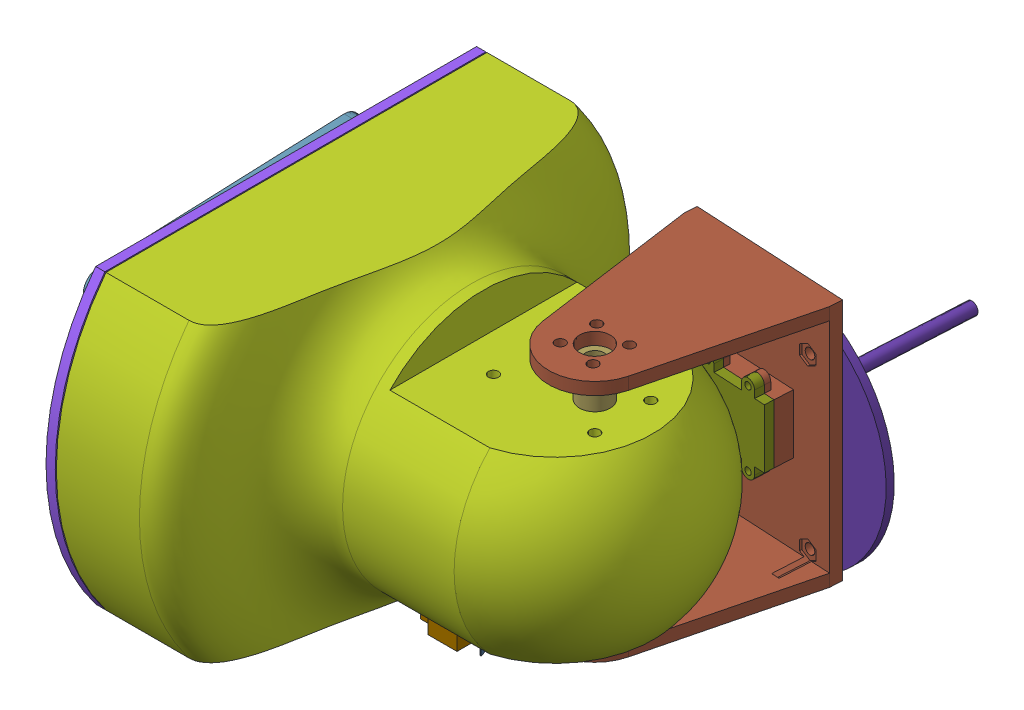
SolidWorks assembly 太阳追踪器, configuration 默认. Lengths in mm.
Overall size (166.51 156 196.42).
44 component instances, 17 part files, 44 mates.
Components (placement in the parent):
- solar_tracer.step-1: solar_tracer.step [默认] at (-191.2949 -153.4039 81.4221) x (0 0 1) z (1 0 0) size (45.95 61.34 13.6)
  - 2.54mm 1x4P.step-1: 2.54mm 1x4P.step [默认] at (-1.796 0.445 0.15) x (0 1 0) z (0 0 1) size (12.02 8.1 13.6)
    - COMPOUND.step-1: COMPOUND.step [默认] at origin size (12.02 8.1 13.6)
  - 2.54mm 1x4P.step-2: 2.54mm 1x4P.step [默认] at (33.272 -1.747 0.15) x (-1 0 0) z (0 0 1) size (12.02 8.1 13.6)
    - COMPOUND.step-1: COMPOUND.step [默认] at origin size (12.02 8.1 13.6)
  - ESP32-S3-WROOM-1.step-1: ESP32-S3-WROOM-1.step [默认] at (20.25 48 1.65) x (0 -1 0) z (0 0 1) size (18 25.5 3.1)
    - COMPOUND-0.step-1: COMPOUND-0.step [默认] at origin size (18 25.5 3.1)
  - 2.54mm 1x2P.step-1: 2.54mm 1x2P.step [默认] at (-1.8 17.8125 0.15) x (0 1 0) z (0 0 1) size (6.95 8.1 13.6)
    - COMPOUND-1.step-1: COMPOUND-1.step [默认] at origin size (6.95 8.1 13.6)
  - 2.54mm 1x2P.step-2: 2.54mm 1x2P.step [默认] at (9.537 62.812 0.15) size (6.95 8.1 13.6)
    - COMPOUND-1.step-1: COMPOUND-1.step [默认] at origin size (6.95 8.1 13.6)
  - 2.54mm 1x4P.step-3: 2.54mm 1x4P.step [默认] at (-1.796 27.7513 0.15) x (0 1 0) z (0 0 1) size (12.02 8.1 13.6)
    - COMPOUND.step-1: COMPOUND.step [默认] at origin size (12.02 8.1 13.6)
  - 2.54mm 1x2P.step-3: 2.54mm 1x2P.step [默认] at (-1.8 10.4038 0.15) x (0 1 0) z (0 0 1) size (6.95 8.1 13.6)
    - COMPOUND-1.step-1: COMPOUND-1.step [默认] at origin size (6.95 8.1 13.6)
  - solar_tracer PCB.step-1: solar_tracer PCB.step [默认] at origin size (40 61 1.6)
- 2814300907JGY-370编码器.STEP-1: 2814300907JGY-370编码器.STEP [默认] at (-155.7925 -163.2626 64.545) size (84.5 46.28 37.08)
  - JGY-370 -636.STEP-1: JGY-370 -636.STEP [默认] at (41.3412 1.3595 0) size (46 38.5 32)
  - 370______.STEP-1: 370______.STEP [默认] at (-12.4588 -9.7405 2.5) x (1 0 0) z (0 -0.481816 0.876272) size (50 24.4 26.7)
- 上壳-1: 上壳 [默认] at (-146.4513 -183.9031 64.495) x (0 0 1) z (0 1 0) size (156 127 156)
- 2814300907JGY-370编码器.STEP-2: 2814300907JGY-370编码器.STEP [默认] at (-198.4354 -183.9031 15.1538) x (0 0 1) z (0 -1 0) size (84.5 46.28 37.08)
  - JGY-370 -636.STEP-1: JGY-370 -636.STEP [默认] at (41.3412 1.3595 0) size (46 38.5 32)
  - 370______.STEP-1: 370______.STEP [默认] at (-12.4588 -9.7405 2.5) x (1 0 0) z (0 -0.481816 0.876272) size (50 24.4 26.7)
- 底板-1: 底板 [默认] at (-206.7949 -183.9031 64.495) x (0 1 0) z (0 0 -1) size (95 7.8 156)
- SS_01GL_E.step-1: SS_01GL_E.step [默认] at (-130.7023 -217.1031 42.1141) x (0 0 -1) z (0 -1 0) size (19.8 20 6.4)
  - SS_01GL_E_BASE.step-1: SS_01GL_E_BASE.step [默认] at origin size (19.8 14.87 6.4)
  - SS_01GL_E_ACTUATOR.step-1: SS_01GL_E_ACTUATOR.step [默认] at (-11.5 7.7 0) size (15.84 5.9 4)
- U型板-1: U型板 [默认] at (-103.7822 -178.4031 14.6163) x (0.053382 0 -0.998574) z (0 1 0) size (69 50 79)
- SS_01GL_E.step-2: SS_01GL_E.step [默认] at (-130.7023 -217.1031 86.8759) x (0 0 1) z (0 1 0) size (19.8 20 6.4)
  - SS_01GL_E_BASE.step-1: SS_01GL_E_BASE.step [默认] at origin size (19.8 14.87 6.4)
  - SS_01GL_E_ACTUATOR.step-1: SS_01GL_E_ACTUATOR.step [默认] at (-11.5 7.7 0) size (15.84 5.9 4)
- 法兰-1: 法兰 [默认] at (-106.4513 -142.9031 64.545) x (-0.053382 0 0.998574) z (0.998574 0 0.053382) size (22 11.6 22)
- 法兰-2: 法兰 [默认] at (-218.7949 -183.9031 64.495) x (0 -0.678155 -0.734919) z (0 -0.734919 0.678155) size (22 11.6 22)
- SS_01GL_E.step-3: SS_01GL_E.step [默认] at (-209.9949 -172.6539 95.4221) x (0 0.34202 0.939693) z (-1 0 0) size (19.8 20 6.4)
  - SS_01GL_E_BASE.step-1: SS_01GL_E_BASE.step [默认] at origin size (19.8 14.87 6.4)
  - SS_01GL_E_ACTUATOR.step-1: SS_01GL_E_ACTUATOR.step [默认] at (-11.5 7.7 0) size (15.84 5.9 4)
- SS_01GL_E.step-4: SS_01GL_E.step [默认] at (-209.9949 -195.1523 95.4221) x (0 -0.34202 0.939693) z (1 0 0) size (19.8 20 6.4)
  - SS_01GL_E_BASE.step-1: SS_01GL_E_BASE.step [默认] at origin size (19.8 14.87 6.4)
  - SS_01GL_E_ACTUATOR.step-1: SS_01GL_E_ACTUATOR.step [默认] at (-11.5 7.7 0) size (15.84 5.9 4)
- pcb支架-1: pcb支架 [默认] at (-193.7949 -183.9039 101.4221) x (0 -1 0) z (-1 0 0) size (71 76 12.5)
- 底座-1: 底座 [默认] at (-226.7949 -183.9031 64.495) x (0 -0.999194 -0.040138) z (0 -0.040138 0.999194) size (57 8 90)
- 轴套-1: 轴套 [默认] at (-106.4513 -217.9031 64.495) x (0.904343 0 0.426806) z (-0.426806 0 0.904343) size (9.7 5 9.7)
- imu盖板-1: imu盖板 [默认] at (-104.1025 -178.4031 20.6078) x (0 1 0) z (-0.053382 0 0.998574) size (28.5 25.2 6)
- 太阳指向盘-1: 太阳指向盘 [默认] at (-103.5687 -183.9031 10.622) x (0 -1 0) z (0.053382 0 -0.998574) size (80 80 62.5)
Mates (geometry in assembly coordinates):
- 同心6: concentric anti-aligned: cylinder of 2814300907JGY-370编码器.STEP-1/JGY-370 -636.STEP-1 through (-97.4513 -157.9031 73.595) axis (0 1 0) radius 1.25; cylinder of 上壳-1 through (-97.4513 -105.9031 73.595) axis (0 -1 0) radius 1.65
- 平行4: parallel anti-aligned: plane of 2814300907JGY-370编码器.STEP-1/JGY-370 -636.STEP-1 through (-137.4513 -182.4031 78.545) normal (-1 0 0); plane of 上壳-1 through (-142.7023 -141.9031 -13.505) normal (1 0 0)
- 重合5: coincident anti-aligned: plane of 2814300907JGY-370编码器.STEP-1/JGY-370 -636.STEP-1 through (-130.5513 -157.9031 55.495) normal (0 1 0); plane of 上壳-1 through (-119.4513 -157.9031 64.495) normal (0 -1 0)
- 同心11: concentric anti-aligned: cylinder of 上壳-1 through (-146.4513 -183.9031 64.495) axis (-1 0 0) radius 42; cylinder of 2814300907JGY-370编码器.STEP-2/JGY-370 -636.STEP-1 through (-217.2949 -183.9031 64.495) axis (1 0 0) radius 3
- 平行6: parallel aligned: plane of 上壳-1 through (-157.5128 -229.4031 64.4207) normal (0 1 0); plane of 2814300907JGY-370编码器.STEP-2/JGY-370 -636.STEP-1 through (-179.2949 -167.9031 35.495) normal (0 1 0)
- 同心12: concentric aligned: cylinder of 上壳-1 through (-146.4513 -183.9031 64.495) axis (-1 0 0) radius 76.3; cylinder of 底板-1 through (-198.9949 -183.9031 64.495) axis (-1 0 0) radius 75.8
- 平行7: parallel aligned: plane of 上壳-1 through (-203.4513 -136.4031 2.6262) normal (0 1 0); plane of 底板-1 through (-198.9949 -138.6031 64.495) normal (0 1 0)
- 重合9: coincident anti-aligned: plane of 2814300907JGY-370编码器.STEP-2/JGY-370 -636.STEP-1 through (-203.7949 -174.8531 73.495) normal (-1 0 0); plane of 底板-1 through (-203.7949 -183.9031 64.495) normal (1 0 0)
- 同心13: concentric anti-aligned: cylinder of 2814300907JGY-370编码器.STEP-1/JGY-370 -636.STEP-1 through (-106.4513 -144.4031 64.545) axis (0 -1 0) radius 3; cylinder of U型板-1 through (-106.4513 -142.9031 64.545) axis (0 1 0) radius 5
- 同心14: concentric anti-aligned: cylinder of 2814300907JGY-370编码器.STEP-1/JGY-370 -636.STEP-1 through (-106.4513 -144.4031 64.545) axis (0 -1 0) radius 3; cylinder of 法兰-1 through (-106.4513 -142.9031 64.545) axis (0 1 0) radius 5
- 重合11: coincident anti-aligned: plane of U型板-1 through (-106.4513 -142.9031 64.545) normal (0 -1 0); plane of 法兰-1 through (-106.6114 -142.9031 67.5408) normal (0 1 0)
- 距离2: distance = 13 mm anti-aligned: plane of 2814300907JGY-370编码器.STEP-1/JGY-370 -636.STEP-1 through (-97.4513 -157.9031 55.495) normal (0 1 0); plane of 法兰-1 through (-107.0385 -144.9031 75.5293) normal (0 -1 0)
- 同心15: concentric anti-aligned: cylinder of 2814300907JGY-370编码器.STEP-2/JGY-370 -636.STEP-1 through (-217.2949 -183.9031 64.495) axis (1 0 0) radius 3; cylinder of 法兰-2 through (-218.7949 -183.9031 64.495) axis (-1 0 0) radius 5
- 距离3: distance = 13 mm anti-aligned: plane of 2814300907JGY-370编码器.STEP-2/JGY-370 -636.STEP-1 through (-203.7949 -174.8531 73.495) normal (-1 0 0); plane of 法兰-2 through (-216.7949 -191.3628 56.4109) normal (1 0 0)
- 重合20: coincident anti-aligned: plane of 底板-1 through (-206.7949 -183.9031 64.495) normal (-1 0 0); plane of SS_01GL_E.step-3/SS_01GL_E_BASE.step-1 through (-206.7949 -173.2247 101.1636) normal (1 0 0)
- 同心16: concentric anti-aligned: cylinder of 上壳-1 through (-130.7023 -206.6504 86.8759) axis (0 -1 0) radius 1.15; cylinder of SS_01GL_E.step-2/SS_01GL_E_BASE.step-1 through (-130.7023 -220.3031 86.8759) axis (0 1 0) radius 1.175
- 同心17: concentric anti-aligned: cylinder of 上壳-1 through (-130.7023 -206.6504 77.3759) axis (0 -1 0) radius 1.15; cylinder of SS_01GL_E.step-2/SS_01GL_E_BASE.step-1 through (-130.7023 -220.3031 77.3759) axis (0 1 0) radius 1.25
- 同心18: concentric aligned: cylinder of 上壳-1 through (-130.7023 -206.6504 42.1141) axis (0 -1 0) radius 1.15; cylinder of SS_01GL_E.step-1/SS_01GL_E_BASE.step-1 through (-130.7023 -213.9031 42.1141) axis (0 -1 0) radius 1.175
- 同心19: concentric aligned: cylinder of 上壳-1 through (-130.7023 -206.6504 51.6141) axis (0 -1 0) radius 1.15; cylinder of SS_01GL_E.step-1/SS_01GL_E_BASE.step-1 through (-130.7023 -213.9031 51.6141) axis (0 -1 0) radius 1.25
- 重合22: coincident anti-aligned: plane of 上壳-1 through (-125.7023 -213.9031 35.1012) normal (0 -1 0); plane of SS_01GL_E.step-2/SS_01GL_E_BASE.step-1 through (-133.2023 -213.9031 92.0759) normal (0 1 0)
- 重合23: coincident anti-aligned: plane of 上壳-1 through (-125.7023 -213.9031 35.1012) normal (0 -1 0); plane of SS_01GL_E.step-1/SS_01GL_E_BASE.step-1 through (-133.2023 -213.9031 36.9141) normal (0 1 0)
- 同心20: concentric aligned: cylinder of 底板-1 through (-198.9949 -175.9031 86.495) axis (-1 0 0) radius 1.15; cylinder of SS_01GL_E.step-3/SS_01GL_E_BASE.step-1 through (-206.7949 -175.9031 86.495) axis (-1 0 0) radius 1.25
- 同心21: concentric aligned: cylinder of 底板-1 through (-198.9949 -172.6539 95.4221) axis (-1 0 0) radius 1.15; cylinder of SS_01GL_E.step-3/SS_01GL_E_BASE.step-1 through (-206.7949 -172.6539 95.4221) axis (-1 0 0) radius 1.175
- 同心23: concentric anti-aligned: cylinder of 底板-1 through (-198.9949 -191.9031 86.495) axis (-1 0 0) radius 1.15; cylinder of SS_01GL_E.step-4/SS_01GL_E_BASE.step-1 through (-213.1949 -191.9031 86.495) axis (1 0 0) radius 1.25
- 重合24: coincident anti-aligned: plane of 底板-1 through (-206.7949 -183.9031 64.495) normal (-1 0 0); plane of SS_01GL_E.step-4/SS_01GL_E_BASE.step-1 through (-206.7949 -194.5816 101.1636) normal (1 0 0)
- 同心24: concentric anti-aligned: cylinder of 底板-1 through (-198.9949 -195.1523 95.4221) axis (-1 0 0) radius 1.15; cylinder of SS_01GL_E.step-4/SS_01GL_E_BASE.step-1 through (-213.1949 -195.1523 95.4221) axis (1 0 0) radius 1.175
- 重合28: coincident anti-aligned: plane of 底板-1 through (-203.7949 -183.9031 64.495) normal (1 0 0); plane of pcb支架-1 through (-203.7949 -198.4039 99.4221) normal (-1 0 0)
- 同心25: concentric aligned: cylinder of 底板-1 through (-198.9949 -172.6539 95.4221) axis (-1 0 0) radius 1.15; cylinder of pcb支架-1 through (-191.2949 -172.6539 95.4221) axis (-1 0 0) radius 1.15
- 平行10: parallel anti-aligned: plane of 底板-1 through (-112.3429 -227.2031 84.495) normal (0 0 1); plane of pcb支架-1 through (-203.7949 -198.4039 91.4221) normal (0 0 -1)
- 同心28: concentric aligned: cylinder of solar_tracer.step-1/solar_tracer PCB.step-1 through (-192.0949 -157.4039 117.4221) axis (1 0 0) radius 1.6; cylinder of pcb支架-1 through (-197.7949 -157.4039 117.4221) axis (1 0 0) radius 1.65
- 同心29: concentric aligned: cylinder of solar_tracer.step-1/solar_tracer PCB.step-1 through (-192.0949 -210.4039 117.4221) axis (1 0 0) radius 1.6; cylinder of pcb支架-1 through (-197.7949 -210.4039 117.4221) axis (1 0 0) radius 1.65
- 重合31: coincident anti-aligned: plane of solar_tracer.step-1/solar_tracer PCB.step-1 through (-191.2949 -183.9039 101.4221) normal (-1 0 0); plane of pcb支架-1 through (-191.2949 -210.4039 117.4221) normal (1 0 0)
- 同心30: concentric aligned: cylinder of U型板-1 through (-112.3685 -142.9031 69.8617) axis (0 1 0) radius 1.65; cylinder of 法兰-1 through (-112.3685 -154.5031 69.8617) axis (0 1 0) radius 1.65
- 同心31: concentric aligned: cylinder of 法兰-2 through (-207.1949 -191.8517 64.1757) axis (-1 0 0) radius 1.65; cylinder of 底座-1 through (-210.3096 -191.8517 64.1757) axis (-1 0 0) radius 3
- 重合32: coincident anti-aligned: plane of 法兰-2 through (-218.7949 -185.9376 62.2903) normal (-1 0 0); plane of 底座-1 through (-218.7949 -183.9031 64.495) normal (1 0 0)
- 同心32: concentric aligned: cylinder of 法兰-2 through (-207.1949 -175.9546 64.8143) axis (-1 0 0) radius 1.65; cylinder of 底座-1 through (-218.7949 -175.9546 64.8143) axis (-1 0 0) radius 1.65
- 同心33: concentric aligned: cylinder of 上壳-1 through (-106.4513 -198.448 64.495) axis (0 -1 0) radius 4.05; cylinder of 轴套-1 through (-106.4513 -212.9031 64.495) axis (0 -1 0) radius 3.925
- 重合33: coincident anti-aligned: plane of 上壳-1 through (-142.7023 -212.9031 -13.505) normal (0 -1 0); plane of 轴套-1 through (-106.4513 -212.9031 64.495) normal (0 1 0)
- 重合34: coincident anti-aligned: plane of U型板-1 through (-104.1025 -178.4031 20.6078) normal (-0.053382 0 0.998574); plane of imu盖板-1 through (-104.1025 -178.4031 20.6078) normal (0.053382 0 -0.998574)
- 同心42: concentric aligned: cylinder of U型板-1 through (-121.0437 -156.4031 9.6878) axis (-0.053382 0 0.998574) radius 1.65; cylinder of 太阳指向盘-1 through (-120.9103 -156.4031 7.1914) axis (-0.053382 0 0.998574) radius 1.65
- 同心43: concentric aligned: cylinder of U型板-1 through (-86.0936 -211.4031 11.5562) axis (-0.053382 0 0.998574) radius 1.65; cylinder of 太阳指向盘-1 through (-85.9602 -211.4031 9.0598) axis (-0.053382 0 0.998574) radius 1.65
- 重合35: coincident anti-aligned: plane of U型板-1 through (-103.5687 -178.4031 10.622) normal (0.053382 0 -0.998574); plane of 太阳指向盘-1 through (-103.5687 -183.9031 10.622) normal (-0.053382 0 0.998574)
- 同心44: concentric aligned: cylinder of U型板-1 through (-97.0057 -190.4031 18.9843) axis (-0.053382 0 0.998574) radius 1.1; cylinder of imu盖板-1 through (-97.1125 -190.4031 20.9814) axis (-0.053382 0 0.998574) radius 1.1
- 同心45: concentric aligned: cylinder of U型板-1 through (-110.9858 -166.4031 18.2369) axis (-0.053382 0 0.998574) radius 1.1; cylinder of imu盖板-1 through (-111.0925 -166.4031 20.2341) axis (-0.053382 0 0.998574) radius 1.1
